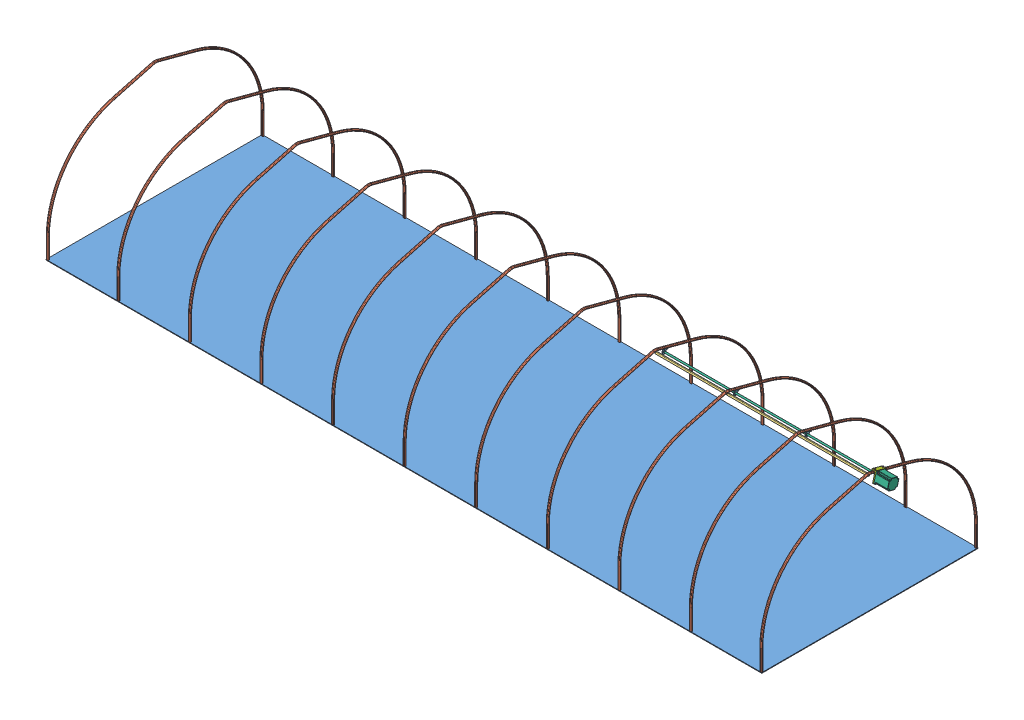
SolidWorks assembly Greenhouse, configuration Default. Lengths in mm.
Overall size (31100.8 5099.94 9207.5).
34 component instances, 7 part files, 68 mates.
Components (placement in the parent):
- Base 2-1: Base 2 [Default] at (10136.1399 15684.6804 24201.437) size (30480 25.4 9207.5)
- Arch-1: Arch [Default] at (25306.3916 15710.0804 28773.437) size (101.4 5043.5 9207.5)
- Arch-2: Arch [Default] at (22309.0899 15710.0801 28773.437) x (1 0.000015 0) z (0 0 1) size (101.4 5043.5 9207.5)
- Arch-3: Arch [Default] at (19261.0899 15710.0804 28773.437) size (101.4 5043.5 9207.5)
- Arch-8: Arch [Default] at (16213.0899 15710.0804 28773.437) size (101.4 5043.5 9207.5)
- Arch-10: Arch [Default] at (13165.0899 15710.0804 28773.437) size (101.4 5043.5 9207.5)
- Arch-11: Arch [Default] at (10117.0899 15710.0804 28773.437) size (101.4 5043.5 9207.5)
- Arch-12: Arch [Default] at (7069.0899 15710.0804 28773.437) size (101.4 5043.5 9207.5)
- Arch-13: Arch [Default] at (4021.0899 15710.0804 28773.437) size (101.4 5043.5 9207.5)
- Arch-14: Arch [Default] at (973.0899 15710.0804 28773.437) size (101.4 5043.5 9207.5)
- Arch-15: Arch [Default] at (-2074.9101 15710.0804 28773.437) size (101.4 5043.5 9207.5)
- Arch-16: Arch [Default] at (-5072.2119 15710.0804 28773.437) size (101.4 5043.5 9207.5)
- Beam-3: Beam [Default] at (25325.2675 20658.2948 24182.387) x (0 0 1) z (0.000015 -1 0) size (101.6 2997.2 63.5)
- heavy hex bolt_ai-9: heavy hex bolt_ai [HHBOLT 0.5000-20x0.5x0.5-N] at (25306.2173 20669.3537 24182.387) x (-0.000015 1 0) z (0 0 1) size (21.95 25.66 22.23)
- heavy hex bolt_ai-10: heavy hex bolt_ai [HHBOLT 0.5000-20x0.5x0.5-N] at (25306.2173 20669.3537 24220.487) x (-0.000015 1 0) z (0 0 1) size (21.95 25.66 22.23)
- heavy hex bolt_ai-12: heavy hex bolt_ai [HHBOLT 0.5000-20x0.5x0.5-N] at (25344.3899 20680.8325 24182.387) x (0 1 0) z (0 0 1) size (21.95 25.66 22.23)
- heavy hex bolt_ai-14: heavy hex bolt_ai [HHBOLT 0.5000-20x0.5x0.5-N] at (25344.3899 20680.8325 24220.487) x (0 1 0) z (0 0 1) size (21.95 25.66 22.23)
- shaft roller bearing-1: shaft roller bearing [Default] at (25310.4416 20588.1364 23874.3014) x (0 -0.257663 -0.966235) z (0 -0.966235 0.257663) size (240 68.1 205.28)
- shaft roller bearing-2: shaft roller bearing [Default] at (22313.0685 20588.1364 23874.3014) x (0.000004 -0.257663 -0.966235) z (0.000014 -0.966235 0.257663) size (240 68.1 205.28)
- shaft roller bearing-3: shaft roller bearing [Default] at (19295.1399 20549.487 23729.3662) x (0 0.257663 0.966235) z (0 -0.966235 0.257663) size (240 68.1 205.28)
- shaft roller bearing-4: shaft roller bearing [Default] at (16217.1399 20588.1364 23874.3014) x (0 -0.257663 -0.966235) z (0 -0.966235 0.257663) size (240 68.1 205.28)
- sketchy-stepper-1: sketchy-stepper [По умолчанию] at (25648.5904 20484.2662 23824.3793) x (0 0.257663 0.966235) z (0 0.966235 -0.257663) size (430 9724 465)
- Sketchy Holder-1: Sketchy Holder [Default] at (25426.9399 20493.0334 23822.1641) x (-1 0 0) z (0 -0.257663 -0.966235) size (177.8 448.06 429.77)
- heavy hex bolt_ai-17: heavy hex bolt_ai [HHBOLT 1.2500-12x1.25x1.25-N] at (25499.1903 20607.6263 23611.4055) x (-1 0 0) z (0 0.924225 0.381849) size (54 58.66 50.8)
- heavy hex bolt_ai-18: heavy hex bolt_ai [HHBOLT 1.2500-12x1.25x1.25-N] at (25499.1903 20697.2929 23947.6552) x (-1 0 0) z (0 0.924225 0.381849) size (54 58.66 50.8)
- heavy hex bolt_ai-19: heavy hex bolt_ai [HHBOLT 1.2500-12x1.25x1.25-N] at (25325.3399 20776.3479 23928.7763) x (0 -0.966235 0.257663) z (-0.257663 0.248963 0.93361) size (54 58.66 50.8)
- heavy hex bolt_ai-20: heavy hex bolt_ai [HHBOLT 1.2500-12x1.25x1.25-N] at (25325.3399 20685.6445 23588.6383) x (0 -0.966235 0.257663) z (-0.257663 0.248963 0.93361) size (54 58.66 50.8)
- heavy hex bolt_ai-21: heavy hex bolt_ai [HHBOLT 1.2500-12x1.25x1.25-N] at (25499.1903 20361.0432 24037.3218) x (-1 0 0) z (0 0.924225 0.381849) size (54 58.66 50.8)
- heavy hex bolt_ai-22: heavy hex bolt_ai [HHBOLT 1.2500-12x1.25x1.25-N] at (25404.6895 20271.3766 23701.0721) size (54 58.66 50.8)
- heavy hex bolt_ai-23: heavy hex bolt_ai [HHBOLT 1.2500-12x1.25x1.25-N] at (25480.9403 20271.3766 23701.0721) x (-1 0 0) z (0 0.924225 0.381849) size (54 58.66 50.8)
- heavy hex bolt_ai-24: heavy hex bolt_ai [HHBOLT 0.5000-13x1.25x1.25-N] at (22347.1173 20669.3105 24182.387) x (-0.000015 1 0) z (0 0 1) size (41 25.66 22.23)
- heavy hex bolt_ai-25: heavy hex bolt_ai [HHBOLT 0.5000-13x1.25x1.25-N] at (22347.1173 20669.3105 24220.487) x (-0.000015 1 0) z (0 0 1) size (41 25.66 22.23)
- Beam-4: Beam [Default] at (19330.8675 20658.9257 24220.487) x (0 0 -1) z (0.000015 -1 0) size (101.6 2997.2 63.5)
- Beam-5: Beam [Default] at (19280.1399 20658.3281 24182.387) x (0 0 1) z (0 -1 0) size (101.6 2997.2 63.5)
Mates (geometry in assembly coordinates):
- Concentric15: concentric anti-aligned: cylinder of Beam-3 through (22347.1899 20664.6013 24220.487) axis (0 1 0) radius 6.35; cylinder of Arch-2 through (22347.1899 20702.7781 24220.487) axis (0 -1 0) radius 6.35
- Concentric16: concentric anti-aligned: cylinder of Beam-3 through (22347.1899 20664.6013 24182.387) axis (0 1 0) radius 6.35; cylinder of Arch-2 through (22347.1899 20702.7781 24182.387) axis (0 -1 0) radius 6.35
- Concentric21: concentric anti-aligned: cylinder of Beam-3 through (25306.2899 20664.6013 24182.387) axis (0 1 0) radius 6.35; cylinder of heavy hex bolt_ai-9 through (25306.2899 20669.3105 24182.387) axis (0 -1 0) radius 6.35
- Coincident40: coincident anti-aligned: plane of Beam-3 through (22328.1399 20678.5561 24182.387) normal (0 -1 0); plane of heavy hex bolt_ai-9 through (25293.4583 20678.5561 24182.387) normal (0 1 0)
- Concentric22: concentric anti-aligned: cylinder of Beam-3 through (25306.2899 20664.6013 24220.487) axis (0 1 0) radius 6.35; cylinder of heavy hex bolt_ai-10 through (25306.2899 20669.3105 24220.487) axis (0 -1 0) radius 6.35
- Coincident41: coincident anti-aligned: plane of Beam-3 through (22328.1399 20678.5561 24182.387) normal (0 -1 0); plane of heavy hex bolt_ai-10 through (25293.4583 20678.5561 24220.487) normal (0 1 0)
- Coincident12: coincident anti-aligned: line of Base 2-1 through (-5103.8601 15710.0804 28805.187) axis (1 0 0); line of Arch-1 through (25344.4916 15710.0804 28805.187) axis (-1 0 0)
- Coincident13: coincident: line of Base 2-1 through (25376.1399 15710.0804 28805.187) axis (0 0 -1); point of Arch-1
- Coincident14: coincident: line of Base 2-1 through (25376.1399 15710.0804 28805.187) axis (0 0 -1); point of Arch-1
- Coincident15: coincident anti-aligned: line of Base 2-1 through (25376.1399 15710.0804 19597.687) axis (-1 0 0); line of Arch-1 through (25306.3916 15710.0804 19597.687) axis (1 0 0)
- Coincident16: coincident anti-aligned: line of Base 2-1 through (-5103.8601 15710.0804 28805.187) axis (1 0 0); line of Arch-16 through (-5034.1119 15710.0804 28805.187) axis (-1 0 0)
- Coincident17: coincident: line of Base 2-1 through (-5103.8601 15710.0804 19597.687) axis (0 0 1)
- Coincident18: coincident anti-aligned: line of Base 2-1 through (25376.1399 15710.0804 19597.687) axis (-1 0 0); line of Arch-16 through (-5072.2119 15710.0804 19597.687) axis (1 0 0)
- Coincident19: coincident: line of Base 2-1 through (-5103.8601 15710.0804 19597.687) axis (0 0 1); point of Arch-16
- Coincident23: coincident: line of Base 2-1 through (992.1399 15710.0804 28805.187) axis (0 0 -1)
- Coincident24: coincident anti-aligned: line of Base 2-1 through (-5103.8601 15710.0804 28805.187) axis (1 0 0); line of Arch-14 through (1011.1899 15710.0804 28805.187) axis (-1 0 0)
- Coincident25: coincident anti-aligned: line of Base 2-1 through (25376.1399 15710.0804 19597.687) axis (-1 0 0); line of Arch-14 through (973.0899 15710.0804 19597.687) axis (1 0 0)
- Perpendicular2: perpendicular: line of Base 2-1 through (-2055.8601 15710.0804 28805.187) axis (0 0 -1); line of Arch-15 through (-2074.9101 15710.0804 28773.437) axis (1 0 0)
- Coincident32: coincident: unknown of Base 2-1; moEndPointRef_w of ?
- Coincident33: coincident: point of assembly; point of Base 2-1; moEndPointRef_w of Arch-3
- Coincident34: coincident: point of assembly; point of Base 2-1; moEndPointRef_w of Arch-8
- Coincident35: coincident: point of assembly; point of Base 2-1; moEndPointRef_w of Arch-10
- Coincident36: coincident: point of assembly; point of Base 2-1; moEndPointRef_w of Arch-11
- Coincident37: coincident: point of assembly; point of Base 2-1; moEndPointRef_w of Arch-12
- Coincident38: coincident: point of assembly; point of Base 2-1; moEndPointRef_w of Arch-13
- Concentric38: concentric aligned: cylinder of Arch-1 through (25344.4916 20583.237 23690.2079) axis (0 -0.966235 0.257663) radius 6.35; cylinder of shaft roller bearing-1 through (25344.4916 20570.9658 23693.4802) axis (0 -0.966235 0.257663) radius 6.35
- Concentric39: concentric aligned: cylinder of Arch-1 through (25306.3916 20583.237 23690.2079) axis (0 -0.966235 0.257663) radius 6.35; cylinder of shaft roller bearing-1 through (25306.3916 20570.9658 23693.4802) axis (0 -0.966235 0.257663) radius 6.35
- Concentric40: concentric aligned: cylinder of Arch-1 through (25344.4916 20636.9029 23891.4553) axis (0 -0.966235 0.257663) radius 6.35; cylinder of shaft roller bearing-1 through (25344.4916 20624.6317 23894.7276) axis (0 -0.966235 0.257663) radius 6.35
- Concentric41: concentric aligned: cylinder of Arch-1 through (25306.3916 20636.9029 23891.4553) axis (0 -0.966235 0.257663) radius 6.35; cylinder of shaft roller bearing-1 through (25306.3916 20624.6317 23894.7276) axis (0 -0.966235 0.257663) radius 6.35
- Coincident39: coincident anti-aligned: plane of Arch-1 through (25306.3916 20243.6172 22465.9231) normal (0 -0.966235 0.257663); plane of shaft roller bearing-1 through (25310.4416 20617.1235 23866.5715) normal (0 0.966235 -0.257663)
- Coincident43: coincident: unknown of Base 2-1; unknown of ?
- Concentric47: concentric aligned: cylinder of Arch-2 through (22347.1899 20636.9029 23891.4553) axis (0 -0.966235 0.257663) radius 6.35; cylinder of shaft roller bearing-2 through (22347.1899 20624.6317 23894.7276) axis (0 -0.966235 0.257663) radius 6.35
- Concentric48: concentric aligned: cylinder of Arch-2 through (22309.0899 20583.237 23690.2079) axis (0 -0.966235 0.257663) radius 6.35; cylinder of shaft roller bearing-2 through (22309.0899 20570.9658 23693.4802) axis (0 -0.966235 0.257663) radius 6.35
- Coincident44: coincident: point of assembly; point of Base 2-1; moEndPointRef_w of Arch-3
- Concentric50: concentric aligned: cylinder of Arch-3 through (19299.1899 20636.9029 23891.4553) axis (0 -0.966235 0.257663) radius 6.35; cylinder of shaft roller bearing-3 through (19299.1899 20624.6317 23894.7276) axis (0 -0.966235 0.257663) radius 6.35
- Concentric51: concentric aligned: cylinder of Arch-3 through (19261.0899 20583.237 23690.2079) axis (0 -0.966235 0.257663) radius 6.35; cylinder of shaft roller bearing-3 through (19261.0899 20570.9658 23693.4802) axis (0 -0.966235 0.257663) radius 6.35
- Coincident45: coincident: point of assembly; point of Base 2-1; moEndPointRef_w of Arch-8
- Concentric52: concentric aligned: cylinder of Arch-8 through (16251.1899 20636.9029 23891.4553) axis (0 -0.966235 0.257663) radius 6.35; cylinder of shaft roller bearing-4 through (16251.1899 20624.6317 23894.7276) axis (0 -0.966235 0.257663) radius 6.35
- Concentric53: concentric aligned: cylinder of Arch-8 through (16213.0899 20583.237 23690.2079) axis (0 -0.966235 0.257663) radius 6.35; cylinder of shaft roller bearing-4 through (16213.0899 20570.9658 23693.4802) axis (0 -0.966235 0.257663) radius 6.35
- Concentric55: concentric aligned: cylinder of shaft roller bearing-1 through (25310.4416 20484.2662 23824.3793) axis (1 0 0) radius 32; cylinder of sketchy-stepper-1 through (43669.9601 23653.5008 24207.3491) axis (-1 0 0) radius 32.004
- Coincident53: coincident anti-aligned: plane of Arch-1 through (25344.4916 20304.9731 22449.5615) normal (0 0.966235 -0.257663); plane of Sketchy Holder-1 through (25249.1399 20603.8176 23570.2285) normal (0 -0.966235 0.257663)
- Coincident54: coincident: line of Arch-1 through (25376.1399 20276.7494 22457.0878) axis (0 0.257663 0.966235); plane of Sketchy Holder-1 through (25376.1399 20493.0334 23822.1641) normal (-1 0 0)
- Parallel19: parallel aligned: line of sketchy-stepper-1 through (34515.9601 23879.1851 24384.6084) axis (0 -0.057753 -0.998331); line of Sketchy Holder-1 through (25426.9399 20657.4018 23569.0832) axis (0 0.257663 0.966235)
- Coincident61: coincident anti-aligned: line of sketchy-stepper-1 through (34515.9601 23830.8368 23981.7282) axis (0 -0.998331 0.057753); line of Sketchy Holder-1 through (25426.9399 20344.2085 24084.2438) axis (0 0.966235 -0.257663)
- Concentric74: concentric anti-aligned: cylinder of sketchy-stepper-1 through (34515.9601 23837.3295 24371.003) axis (1 0 0) radius 16.25; cylinder of heavy hex bolt_ai-17 through (25499.1903 20607.6263 23611.4055) axis (1 0 0) radius 15.875
- Coincident63: coincident anti-aligned: plane of sketchy-stepper-1 through (34465.9601 23474.8611 24407.9984) normal (-1 0 0); plane of heavy hex bolt_ai-17 through (25476.9399 20596.4269 23638.5124) normal (-1 0 0)
- Concentric75: concentric anti-aligned: cylinder of sketchy-stepper-1 through (34515.9601 23817.2314 24023.5838) axis (1 0 0) radius 16.25; cylinder of heavy hex bolt_ai-18 through (25499.1903 20697.2929 23947.6552) axis (1 0 0) radius 15.875
- Coincident64: coincident anti-aligned: plane of sketchy-stepper-1 through (34465.9601 23474.8611 24407.9984) normal (-1 0 0); plane of heavy hex bolt_ai-18 through (25476.9399 20686.0935 23974.7622) normal (-1 0 0)
- Concentric76: concentric aligned: cylinder of Sketchy Holder-1 through (25325.3399 20681.2217 23954.1433) axis (0 0.966235 -0.257663) radius 16.256; cylinder of heavy hex bolt_ai-19 through (25325.3399 20776.3479 23928.7763) axis (0 0.966235 -0.257663) radius 15.875
- Coincident65: coincident anti-aligned: plane of Sketchy Holder-1 through (25376.1399 20709.4971 23764.4404) normal (0 0.966235 -0.257663); plane of heavy hex bolt_ai-19 through (25353.6789 20756.796 23941.8113) normal (0 -0.966235 0.257663)
- Concentric77: concentric aligned: cylinder of Sketchy Holder-1 through (25325.3399 20590.5182 23614.0053) axis (0 0.966235 -0.257663) radius 16.256; cylinder of heavy hex bolt_ai-20 through (25325.3399 20685.6445 23588.6383) axis (0 0.966235 -0.257663) radius 15.875
- Coincident66: coincident anti-aligned: plane of Sketchy Holder-1 through (25376.1399 20709.4971 23764.4404) normal (0 0.966235 -0.257663); plane of heavy hex bolt_ai-20 through (25353.6789 20666.0925 23601.6734) normal (0 -0.966235 0.257663)
- Concentric78: concentric anti-aligned: cylinder of sketchy-stepper-1 through (34515.9601 23469.8122 24043.6819) axis (1 0 0) radius 16.25; cylinder of heavy hex bolt_ai-21 through (25499.1903 20361.0432 24037.3218) axis (1 0 0) radius 15.875
- Coincident67: coincident anti-aligned: plane of sketchy-stepper-1 through (34465.9601 23474.8611 24407.9984) normal (-1 0 0); plane of heavy hex bolt_ai-21 through (25476.9399 20349.8438 24064.4288) normal (-1 0 0)
- Concentric79: concentric aligned: cylinder of sketchy-stepper-1 through (34515.9601 23489.9103 24391.1011) axis (1 0 0) radius 16.25; cylinder of heavy hex bolt_ai-22 through (25404.6895 20271.3766 23701.0721) axis (-1 0 0) radius 15.875
- Coincident68: coincident anti-aligned: plane of sketchy-stepper-1 through (34515.9601 23474.8611 24407.9984) normal (1 0 0); plane of heavy hex bolt_ai-22 through (25426.9399 20300.706 23701.0721) normal (1 0 0)
- Concentric80: concentric aligned: cone of heavy hex bolt_ai-22 through (25458.6899 20271.3766 23701.0721) axis (1 0 0); cylinder of heavy hex bolt_ai-23 through (25480.9403 20271.3766 23701.0721) axis (1 0 0) radius 15.875
- Coincident69: coincident anti-aligned: plane of heavy hex bolt_ai-22 through (25458.6899 20271.3766 23701.0721) normal (1 0 0); plane of heavy hex bolt_ai-23 through (25458.6899 20260.1772 23728.179) normal (-1 0 0)
- Concentric81: concentric anti-aligned: cylinder of Beam-3 through (22347.1899 20664.6013 24182.387) axis (0 1 0) radius 6.35; cylinder of heavy hex bolt_ai-24 through (22347.1173 20669.3105 24182.387) axis (0.000015 -1 0) radius 6.35
- Coincident70: coincident anti-aligned: plane of Beam-3 through (22328.1399 20678.5561 24182.387) normal (0 -1 0); plane of heavy hex bolt_ai-24 through (22334.2856 20678.5559 24182.387) normal (-0.000015 1 0)
- Concentric82: concentric anti-aligned: cylinder of Beam-3 through (22347.1899 20664.6013 24220.487) axis (0 1 0) radius 6.35; cylinder of heavy hex bolt_ai-25 through (22347.1173 20669.3105 24220.487) axis (0.000015 -1 0) radius 6.35
- Coincident71: coincident anti-aligned: plane of Beam-3 through (22328.1399 20678.5561 24182.387) normal (0 -1 0); plane of heavy hex bolt_ai-25 through (22334.2856 20678.5559 24220.487) normal (-0.000015 1 0)
- Concentric84: concentric anti-aligned: cylinder of Arch-2 through (22309.0899 20702.7781 24220.487) axis (0 -1 0) radius 6.35; cylinder of Beam-4 through (22309.0174 20665.3193 24220.487) axis (-0.000015 1 0) radius 6.35
- Concentric85: concentric anti-aligned: cylinder of Arch-2 through (22309.0899 20702.7781 24182.387) axis (0 -1 0) radius 6.35; cylinder of Beam-4 through (22309.0174 20665.3193 24182.387) axis (-0.000015 1 0) radius 6.35
- Tangent1: tangent: curve of Arch-2; circle of Beam-4
- Concentric86: concentric anti-aligned: cylinder of Arch-3 through (19261.0899 20702.7781 24182.387) axis (0 -1 0) radius 6.35; cylinder of Beam-5 through (19261.0899 20664.6781 24182.387) axis (0 1 0) radius 6.35
- Concentric87: concentric anti-aligned: cylinder of Arch-3 through (19261.0899 20702.7781 24220.487) axis (0 -1 0) radius 6.35; cylinder of Beam-5 through (19261.0899 20664.6781 24220.487) axis (0 1 0) radius 6.35
- Coincident72: coincident anti-aligned: circle of Arch-3; circle of Beam-5
